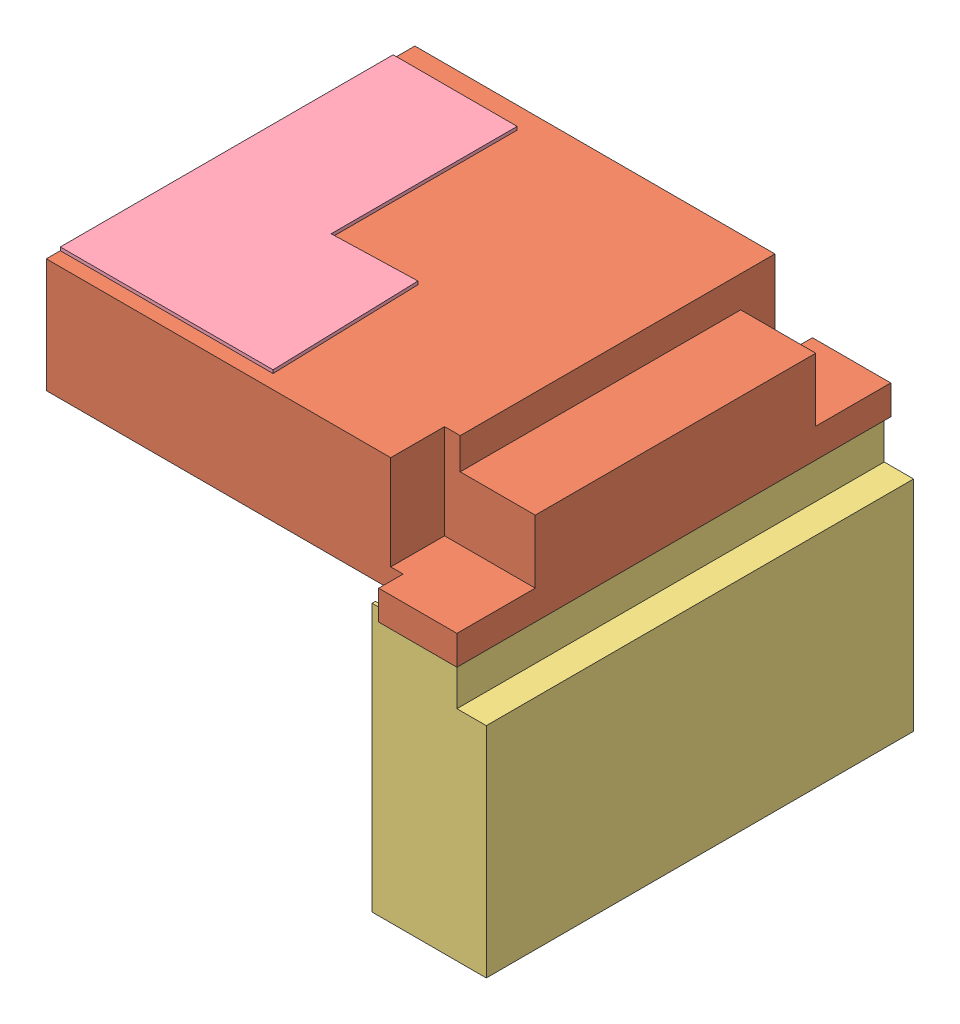
SolidWorks assembly Covers, configuration Default. Lengths in mm.
Overall size (458.6 374.65 431.8).
4 component instances, 4 part files, 5 mates.
Components (placement in the parent):
- Bottom Seal-1: Bottom Seal [Default] at origin size (344.17 19.05 362.9) (hidden)
- Top Cover-1: Top Cover [Default] at (-176.6078 0 140.2448) size (423.54 120.65 422.27)
- Back Cover-1: Back Cover [Default] at (0 -106.0113 194.827) x (0 0 -1) z (1 0 0) size (428.63 260.35 111.12)
- LV Cover-1: LV Cover [Default] at (8.3751 111.125 0.1918) x (0.999556 0 -0.029808) z (0.029808 0 0.999556) size (207.01 3.17 330.02) (hidden)
Mates (geometry in assembly coordinates):
- Distance1: distance = 20.6375 mm anti-aligned: plane of Back Cover-1 through (98.425 0 382.27) normal (0 0 -1); plane of Bottom Seal-1 through (-146.05 0 361.6325) normal (0 0 1)
- Coincident4: coincident anti-aligned: plane of Bottom Seal-1 through (-146.05 0 180.1812) normal (0 -1 0); plane of Back Cover-1 through (98.425 0 382.27) normal (0 1 0)
- Coincident5: coincident anti-aligned: line of Top Cover-1 through (0 15.875 361.6325) axis (0 -1 0); line of Bottom Seal-1 through (0 0 361.6325) axis (0 1 0)
- Coincident7: coincident aligned: plane of Bottom Seal-1 through (-362.6273 0 -1.27) normal (0 -1 0); plane of Top Cover-1 through (-176.6078 0 140.2448) normal (0 -1 0)
- Coincident9: coincident anti-aligned: plane of Top Cover-1 through (73.025 -9.525 -30.48) normal (-1 0 0); plane of Back Cover-1 through (73.025 -50.8 382.27) normal (1 0 0)
